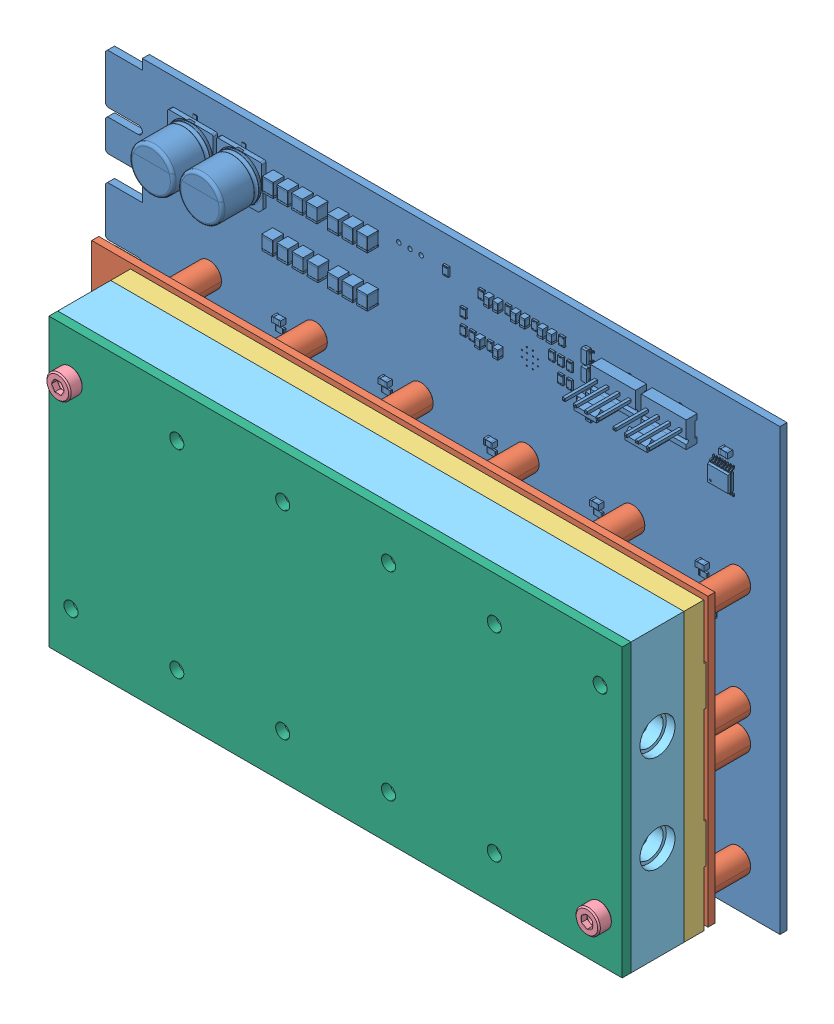
SolidWorks assembly EKO_Miner build 10xBM1370 V1.00, configuration Défaut. Lengths in mm.
Overall size (153 99.75 41.59).
9 component instances, 6 part files, 20 mates.
Components (placement in the parent):
- EKO_Miner_PowerBoard_TPS53667_01A-1: EKO_Miner_PowerBoard_TPS53667_01A [Défaut] at (-199.381 92.9814 -3.14) size (153 99.75 17.02)
- EKO_Miner_AsicBoard-10xBM1370-01A-1: EKO_Miner_AsicBoard-10xBM1370-01A [Défaut] at (-124.381 -27.0186 8.59) size (139.75 65 12.43)
- EKO_Miner_AsicBoard-BM13xx Heatsink Base 01A-1: EKO_Miner_AsicBoard-BM13xx Heatsink Base 01A [Défaut] at (-114.381 -27.0186 10.89) size (130 65 5)
- CHC3 M3x6mm-1: CHC3 M3x6mm [M3X6mm] at (10.619 -22.0186 -6.14) x (0.550717 0.834692 0) z (0 0 -1) size (5.5 5.5 9.19)
- CHC3 M3x6mm-2: CHC3 M3x6mm [M3X6mm] at (-109.381 32.9814 -6.14) x (0.649106 -0.760698 0) z (0 0 -1) size (5.5 5.5 9.19)
- EKO_Miner_AsicBoard-BM13xx Heatsink Version B 01A-1: EKO_Miner_AsicBoard-BM13xx Heatsink Version B 01A [Défaut] at (15.619 37.9814 15.89) x (-1 0 0) z (0 0 1) size (130 65 12)
- EKO_Miner_AsicBoard-BM13xx Heatsink Version B top 01A-1: EKO_Miner_AsicBoard-BM13xx Heatsink Version B top 01A [Défaut] at (15.619 37.9814 27.89) x (-1 0 0) z (0 0 1) size (130 65 2)
- CHC3 M3x6mm-3: CHC3 M3x6mm [M3X6mm] at (-109.381 27.9814 32.89) x (0.857084 0.515176 0) z (0 0 1) size (5.5 5.5 9.19)
- CHC3 M3x6mm-4: CHC3 M3x6mm [M3X6mm] at (10.619 -17.0186 32.89) size (5.5 5.5 9.19)
Mates (geometry in assembly coordinates):
- Coaxiale1: concentric anti-aligned: cylinder of EKO_Miner_PowerBoard_TPS53667_01A-1 through (-109.381 -22.0186 -3.185) axis (0 0 -1) radius 1.6; cylinder of EKO_Miner_AsicBoard-10xBM1370-01A-1 through (-109.381 -22.0186 4.225) axis (0 0 1) radius 1.2295
- Coaxiale2: concentric aligned: cylinder of EKO_Miner_PowerBoard_TPS53667_01A-1 through (10.619 32.9814 -3.185) axis (0 0 -1) radius 1.6; circle of EKO_Miner_AsicBoard-10xBM1370-01A-1
- Coïncidente1: coincident anti-aligned: plane of EKO_Miner_PowerBoard_TPS53667_01A-1 through (-199.381 92.9814 -1.54) normal (0 0 1); plane of EKO_Miner_AsicBoard-10xBM1370-01A-1 through (9.2707 32.9814 -1.54) normal (0 0 -1)
- Coaxiale5: concentric aligned: cylinder of EKO_Miner_PowerBoard_TPS53667_01A-1 through (10.619 -22.0186 -3.185) axis (0 0 -1) radius 1.6; cylinder of CHC3 M3x6mm-1 through (10.619 -22.0186 -6.14) axis (0 0 -1) radius 1.5
- Coïncidente3: coincident anti-aligned: plane of EKO_Miner_PowerBoard_TPS53667_01A-1 through (-199.381 92.9814 -3.14) normal (0 0 -1); plane of CHC3 M3x6mm-1 through (12.735 -23.4147 -3.14) normal (0 0 1)
- Coaxiale6: concentric aligned: cylinder of EKO_Miner_PowerBoard_TPS53667_01A-1 through (-109.381 32.9814 -3.185) axis (0 0 -1) radius 1.6; cylinder of CHC3 M3x6mm-2 through (-109.381 32.9814 -6.14) axis (0 0 -1) radius 1.5
- Coïncidente4: coincident anti-aligned: plane of EKO_Miner_PowerBoard_TPS53667_01A-1 through (-199.381 92.9814 -3.14) normal (0 0 -1); plane of CHC3 M3x6mm-2 through (-111.3093 31.3359 -3.14) normal (0 0 1)
- Coaxiale7: concentric anti-aligned: cylinder of EKO_Miner_AsicBoard-10xBM1370-01A-1 through (-1.381 32.9814 8.545) axis (0 0 -1) radius 1.6; cylinder of EKO_Miner_AsicBoard-BM13xx Heatsink 01A-1 through (-1.381 32.9814 15.89) axis (0 0 1) radius 1.7
- Coaxiale8: concentric anti-aligned: cylinder of EKO_Miner_AsicBoard-10xBM1370-01A-1 through (-97.381 -22.0186 8.545) axis (0 0 -1) radius 1.6; cylinder of EKO_Miner_AsicBoard-BM13xx Heatsink 01A-1 through (-97.381 -22.0186 15.89) axis (0 0 1) radius 1.7
- Coïncidente5: coincident anti-aligned: plane of EKO_Miner_AsicBoard-10xBM1370-01A-1 through (-97.381 -10.0186 10.89) normal (0 0 1); plane of EKO_Miner_AsicBoard-BM13xx Heatsink 01A-1 through (-114.381 -27.0186 10.89) normal (0 0 -1)
- Coaxiale9: concentric anti-aligned: cylinder of EKO_Miner_AsicBoard-BM13xx Heatsink Version B 01A-1 through (-109.381 -17.0186 15.89) axis (0 0 1) radius 1.6; cylinder of EKO_Miner_AsicBoard-BM13xx Heatsink Version B top 01A-1 through (-109.381 -17.0186 29.89) axis (0 0 -1) radius 1.6
- Coaxiale10: concentric anti-aligned: cylinder of EKO_Miner_AsicBoard-BM13xx Heatsink Version B 01A-1 through (10.619 27.9814 15.89) axis (0 0 1) radius 1.6; cylinder of EKO_Miner_AsicBoard-BM13xx Heatsink Version B top 01A-1 through (10.619 27.9814 29.89) axis (0 0 -1) radius 1.6
- Coïncidente6: coincident anti-aligned: plane of EKO_Miner_AsicBoard-BM13xx Heatsink Version B 01A-1 through (15.619 37.9814 27.89) normal (0 0 1); plane of EKO_Miner_AsicBoard-BM13xx Heatsink Version B top 01A-1 through (15.619 37.9814 27.89) normal (0 0 -1)
- Coïncidente7: coincident anti-aligned: plane of EKO_Miner_AsicBoard-BM13xx Heatsink Base 01A-1 through (-114.381 -27.0186 15.89) normal (0 0 1); plane of EKO_Miner_AsicBoard-BM13xx Heatsink Version B 01A-1 through (15.619 37.9814 15.89) normal (0 0 -1)
- Coaxiale13: concentric anti-aligned: cylinder of EKO_Miner_AsicBoard-BM13xx Heatsink Base 01A-1 through (-24.381 5.4814 11.39) axis (0 0 -1) radius 1.7; cylinder of EKO_Miner_AsicBoard-BM13xx Heatsink Version B 01A-1 through (-24.381 5.4814 15.89) axis (0 0 1) radius 1.6
- Coaxiale14: concentric anti-aligned: cylinder of EKO_Miner_AsicBoard-BM13xx Heatsink Base 01A-1 through (-74.381 5.4814 11.39) axis (0 0 -1) radius 1.7; cylinder of EKO_Miner_AsicBoard-BM13xx Heatsink Version B 01A-1 through (-74.381 5.4814 15.89) axis (0 0 1) radius 1.6
- Coaxiale15: concentric aligned: cylinder of EKO_Miner_AsicBoard-BM13xx Heatsink Version B 01A-1 through (-109.381 27.9814 15.89) axis (0 0 1) radius 1.6; cylinder of CHC3 M3x6mm-3 through (-109.381 27.9814 32.89) axis (0 0 1) radius 1.5
- Coïncidente8: coincident anti-aligned: plane of EKO_Miner_AsicBoard-BM13xx Heatsink Version B top 01A-1 through (15.619 37.9814 29.89) normal (0 0 1); plane of CHC3 M3x6mm-3 through (-110.6869 30.1541 29.89) normal (0 0 -1)
- Coaxiale16: concentric aligned: cylinder of EKO_Miner_AsicBoard-BM13xx Heatsink Version B 01A-1 through (10.619 -17.0186 15.89) axis (0 0 1) radius 1.6; cylinder of CHC3 M3x6mm-4 through (10.619 -17.0186 32.89) axis (0 0 1) radius 1.5
- Coïncidente9: coincident anti-aligned: plane of EKO_Miner_AsicBoard-BM13xx Heatsink Version B top 01A-1 through (15.619 37.9814 29.89) normal (0 0 1); plane of CHC3 M3x6mm-4 through (10.619 -14.4836 29.89) normal (0 0 -1)
